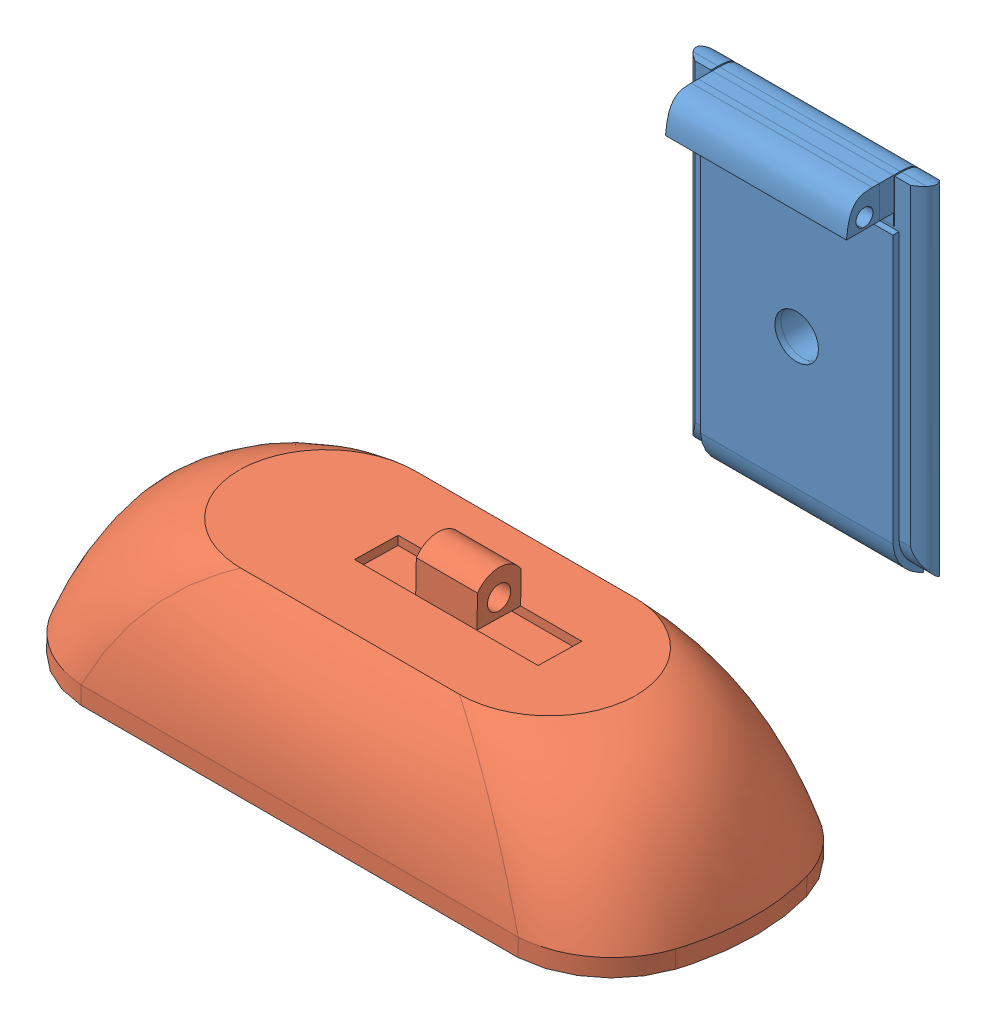
SolidWorks assembly logitech_webcam_c270, configuration Default. Lengths in mm.
Overall size (72.97 45.94 60.15).
3 component instances, 3 part files, 4 mates.
Components (placement in the parent):
- mount_bottom-2: mount_bottom [Default] at (-50.5241 -25.6324 -14.3037) size (28.79 42.01 11.53)
- mount-2: mount [Default] at (-35.3741 -2.0046 30.4909) x (-1 0 0) z (0 -0.881498 -0.472187) size (30.02 47.27 15.02) (hidden)
- logitech_webcam_c270-2: logitech_webcam_c270 [Default] at (-10.626 -27.1278 13.5881) x (-1 0 0) z (0 0.01979 0.999804) size (72.97 22.01 31.05)
Mates (geometry in assembly coordinates):
- Concentric1: concentric anti-aligned: cylinder of mount-2 through (-56.3741 -9.7963 29.1533) axis (1 0 0) radius 1.25; cylinder of logitech_webcam_c270-2 through (-39.3741 -9.7963 29.1533) axis (-1 0 0) radius 1.3325
- Coincident2: coincident anti-aligned: plane of mount-2 through (-46.3741 -9.7963 29.1533) normal (1 0 0); plane of logitech_webcam_c270-2 through (-46.3741 -9.7963 29.1533) normal (-1 0 0)
- Concentric2: concentric aligned: cylinder of mount_bottom-2 through (-32.6741 13.6676 -5.9241) axis (-1 0 0) radius 0.9761; cylinder of mount-2 through (-31.3741 13.6676 -5.9241) axis (-1 0 0) radius 0.9761
- Coincident3: coincident anti-aligned: plane of mount_bottom-2 through (-53.3741 15.4278 -4.7224) normal (-1 0 0); plane of mount-2 through (-53.3741 22.7115 -7.3475) normal (1 0 0)
